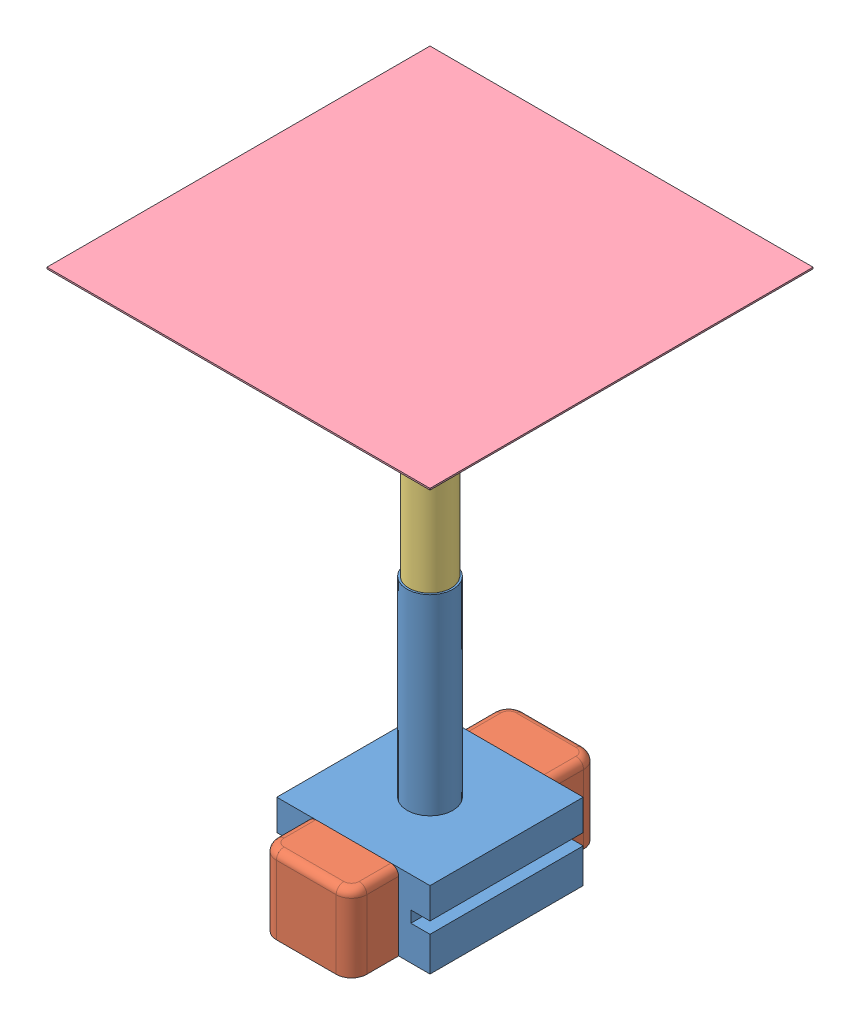
SolidWorks assembly posfasdfale, configuration Default. Lengths in mm.
Overall size (1000 1398.2 1000).
11 component instances, 6 part files, 12 mates.
Components (placement in the parent):
- pilon-1: pilon [Default] at (750.6878 634.4701 2074.8363) size (400 700 400)
- fix-1: fix [Default] at (704.1878 324.4701 2336.3363) size (236 530 123)
  - screw - Copy-1: screw - Copy [Default] at origin size (83 330 83) (hidden)
  - Part3^fix-1: Part3^fix [Default] at origin size (236 200 123) (virtual)
  - screw2 - Copy - Copy-1: screw2 - Copy - Copy [Default] at (97.0846 0 0) size (83 330 83) (hidden)
- fix-2: fix [Default] at (797.1878 324.4701 1813.3363) x (-1 0 0) z (0 0 -1) size (236 530 123)
  - screw - Copy-1: screw - Copy [Default] at origin size (83 330 83) (hidden)
  - Part3^fix-1: Part3^fix [Default] at origin size (236 200 123) (virtual)
  - screw2 - Copy - Copy-1: screw2 - Copy - Copy [Default] at (97.0846 0 0) size (83 330 83) (hidden)
- pilon2-1: pilon2 [Default] at (750.6878 1318.6712 2074.8363) x (0.920349 0 0.391098) z (-0.391098 0 0.920349) size (110 500 110)
- cap-2: cap [Default] at (750.6878 1818.6712 2074.8363) x (0 0 1) z (-1 0 0) size (1000 264 1000)
Mates (geometry in assembly coordinates):
- Coincident2: coincident: plane of pilon-1 through (950.6878 834.4701 2274.8363) normal (0 0 1); plane of fix-1/Part3^fix-1 through (632.6878 834.4701 2274.8363) normal (0 0 -1)
- Width1: width: plane of pilon-1 through (950.6878 834.4701 2274.8363) normal (1 0 0); plane of pilon-1 through (550.6878 834.4701 2274.8363) normal (-1 0 0); plane of fix-1/Part3^fix-1 through (868.6878 834.4701 2357.8363) normal (1 0 0); plane of fix-1/Part3^fix-1 through (632.6878 834.4701 2357.8363) normal (-1 0 0)
- Coincident3: coincident: plane of pilon-1 through (750.6878 634.4701 2074.8363) normal (0 -1 0); plane of fix-1/Part3^fix-1 through (828.6878 634.4701 2357.8363) normal (0 -1 0)
- Coincident4: coincident: plane of pilon-1 through (950.6878 834.4701 1874.8363) normal (0 0 -1); plane of fix-2/Part3^fix-1 through (868.6878 834.4701 1874.8363) normal (0 0 1)
- Width2: width: plane of pilon-1 through (950.6878 834.4701 2274.8363) normal (1 0 0); plane of pilon-1 through (550.6878 834.4701 2274.8363) normal (-1 0 0); plane of fix-2/Part3^fix-1 through (868.6878 834.4701 1791.8363) normal (1 0 0); plane of fix-2/Part3^fix-1 through (632.6878 834.4701 1791.8363) normal (-1 0 0)
- Coincident5: coincident: plane of pilon-1 through (750.6878 634.4701 2074.8363) normal (0 -1 0); plane of fix-2/Part3^fix-1 through (672.6878 634.4701 1791.8363) normal (0 -1 0)
- Concentric1: concentric: cylinder of pilon-1 through (750.6878 2834.4701 2074.8363) axis (0 -1 0) radius 50; cylinder of ? through (750.6878 2784.4701 2074.8363) axis (0 1 0) radius 45
- Coincident6: coincident: plane of pilon-1 through (750.6878 2834.4701 2074.8363) normal (0 1 0); plane of ? through (750.6878 2834.4701 2074.8363) normal (0 -1 0)
- Concentric2: concentric: cylinder of pilon-1 through (750.6878 1334.4701 2074.8363) axis (0 -1 0) radius 55; cylinder of pilon2-1 through (750.6878 1818.6712 2074.8363) axis (0 -1 0) radius 55
- Concentric3: concentric: cylinder of pilon2-1 through (750.6878 1818.6712 2074.8363) axis (0 -1 0) radius 50; cylinder of cap-2 through (750.6878 1768.6712 2074.8363) axis (0 1 0) radius 45
- Coincident7: coincident: plane of pilon2-1 through (750.6878 1818.6712 2074.8363) normal (0 1 0); plane of cap-2 through (750.6878 1818.6712 2074.8363) normal (0 -1 0)
- Parallel2: parallel: plane of pilon-1 through (950.6878 834.4701 2274.8363) normal (1 0 0); plane of cap-2 through (1250.6878 2032.6712 1574.8363) normal (1 0 0)
